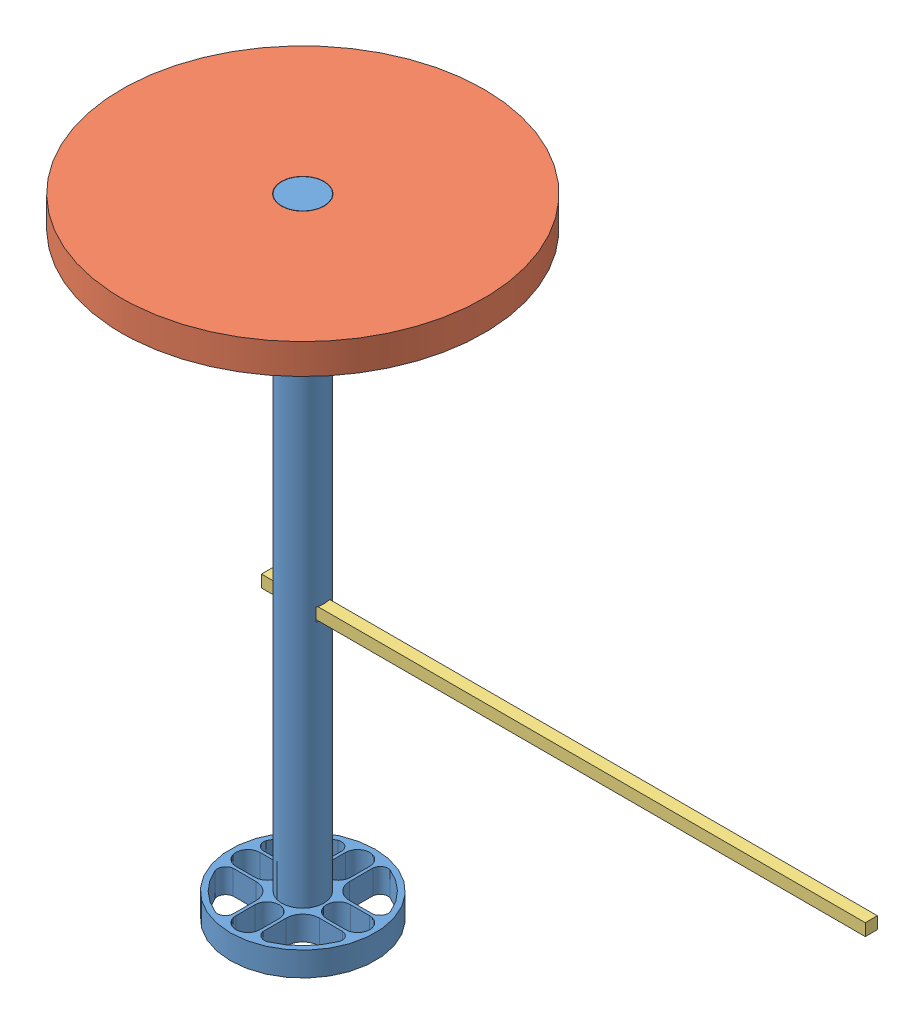
SolidWorks assembly Assem1, configuration Default. Lengths in mm.
Overall size (124.04 104 60).
3 component instances, 3 part files, 4 mates.
Components (placement in the parent):
- Shaft-1: Shaft [Default] at (38.3705 11.3117 73.9254) size (24 104 24)
- Base-1: Base [Default] at (38.3705 110.3117 73.9254) size (60 5 60)
- Moment Arm-1: Moment Arm [Default] at (32.4089 57.2353 73.8132) size (100 2 2)
Mates (geometry in assembly coordinates):
- Concentric1: concentric aligned: circle of Shaft-1; circle of Base-1
- Coincident2: coincident aligned: plane of Shaft-1 through (38.3705 115.3117 73.9254) normal (0 1 0); plane of Base-1 through (38.3705 115.3117 73.9254) normal (0 1 0)
- Coincident3: coincident anti-aligned: plane of Shaft-1 through (42.8071 58.2353 75.0377) normal (0 -1 0); plane of Moment Arm-1 through (132.4089 58.2353 74.8132) normal (0 1 0)
- Coincident4: coincident anti-aligned: plane of Shaft-1 through (42.8071 56.0876 72.8132) normal (0 0 1); plane of Moment Arm-1 through (132.4089 56.2353 72.8132) normal (0 0 -1)
